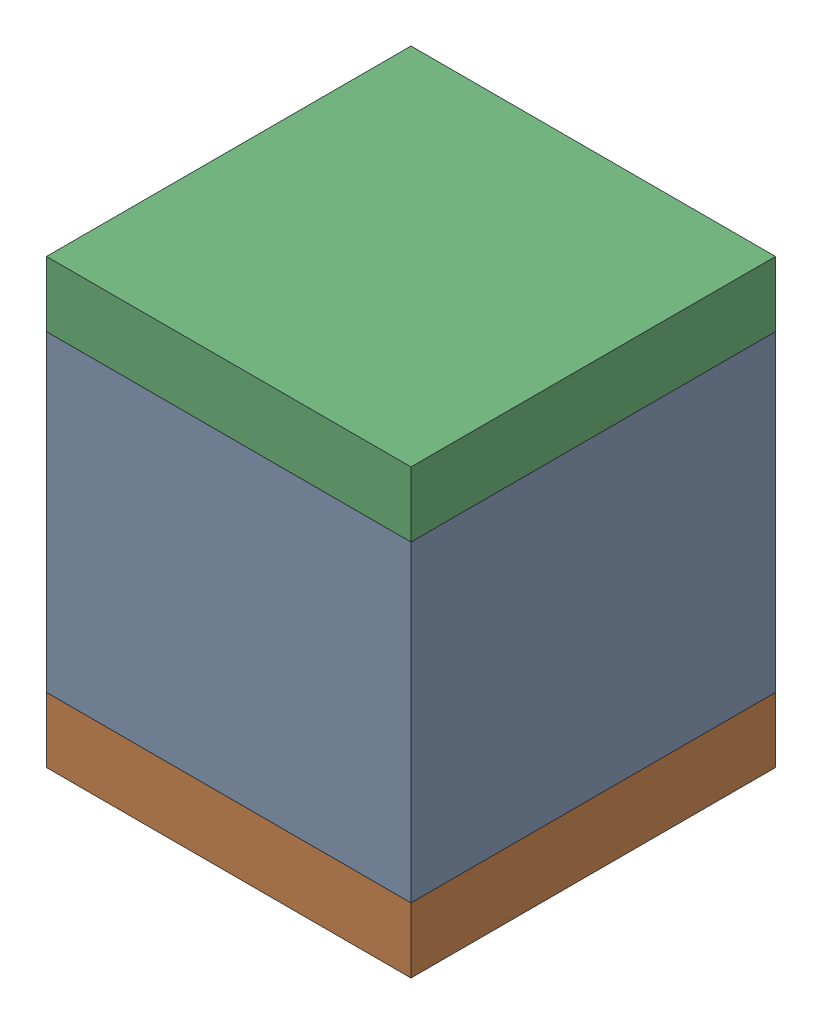
SolidWorks assembly C404PCB, configuration Default. Lengths in mm.
Overall size (2.8 3.4 2.8).
6 component instances, 2 part files, 0 mates.
Components (placement in the parent):
- 846484376-1: 846484376 [Default] at (90.4 82.3 -4.4638) size (2.8 2.4 2.8)
  - Extruded_31-1: Extruded_31 [Default] at origin size (2.8 2.4 2.8)
- 846484512-1: 846484512 [Default] at (90.4 80.85 -4.4638) size (2.8 0.5 2.8)
  - Extruded_32-1: Extruded_32 [Default] at origin size (2.8 0.5 2.8)
- 846484512-2: 846484512 [Default] at (90.4 83.75 -4.4638) size (2.8 0.5 2.8)
  - Extruded_32-1: Extruded_32 [Default] at origin size (2.8 0.5 2.8)
